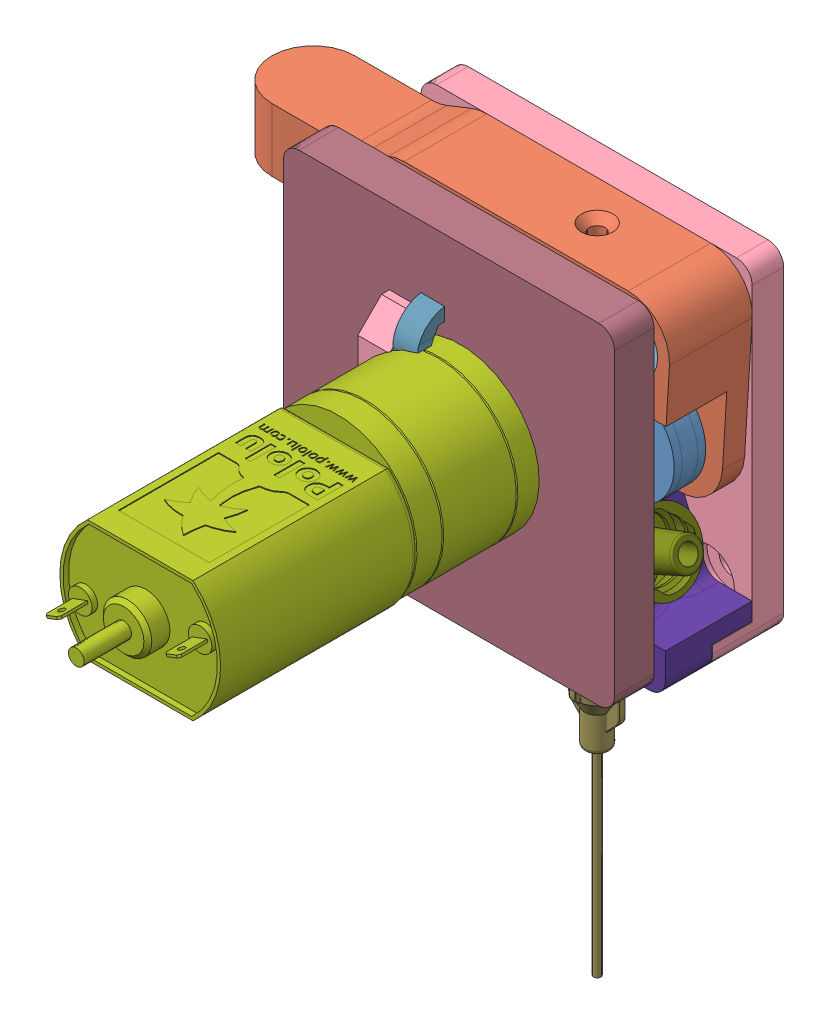
SolidWorks assembly Extruder mini gear motor custom metal liner, configuration Default. Lengths in mm.
Overall size (55.67 53.4 45.47).
19 component instances, 17 part files, 38 mates.
Components (placement in the parent):
- ExtruderCR10 idler-1: ExtruderCR10 idler [Default] at (-21 -21 0) size (13 13 4)
- ExtruderCR10 lever-1: ExtruderCR10 lever [Default] at (-21 -21 0) size (55.67 26.5 10.5)
- ExtruderCR10 spring-1: ExtruderCR10 spring [Default] at (-21 -21 0) size (8.03 21.41 8.04)
- Extruder custom base-1: Extruder custom base [Default] at origin size (42 42 24)
- ExtruderCR10 bushing-1: ExtruderCR10 bushing [Default] at (-21 -21 0) size (8 8 10.5)
- ExtruderCR10 M3-1: ExtruderCR10 M3 [Default] at (-21 -21 0) size (5.58 5.58 7.43)
- 20d-metal-gearmotor-25-31-with-extended-motor-shaft-1: 20d-metal-gearmotor-25-31-with-extended-motor-shaft [Default] at (23.8942 -21.0034 65.0067) x (-1 0 0) z (0 0 -1) size (20.4 20 67.2) (hidden)
- Part1-1: Part1 [Default] at (0 0 -19.7668) size (11.5 11.5 6)
- 94510A360_BRASS SCREW-TO-EXPAND INSERTS FOR PLASTICS-1: 94510A360_BRASS SCREW-TO-EXPAND INSERTS FOR PLASTICS [94510A360] at (-0.5 -16 0) x (0 -1 0) z (1 0 0) size (4.8 4.14 4.77) (hidden)
- 94510A240_BRASS SCREW-TO-EXPAND INSERTS-1: 94510A240_BRASS SCREW-TO-EXPAND INSERTS [94510A240] at (-0.5 -16 0) x (0 1 0) z (-1 0 0) size (5.54 5.05 5.54)
- 52335K910_METRIC EXTREME-TEMP TUBING MADE WITH PTFE-1: 52335K910_METRIC EXTREME-TEMP TUBING MADE WITH PTFE [52335K91] at (6.35 -9.5 9) x (0 1 0) z (0.546944 0 -0.837169) size (15 3 3)
- Syringe Needle, With Luer-1: Syringe Needle, With Luer [Yellow_20Gauge] at (6.35 -36.1851 9) x (0 1 0) z (0 0 1) size (43.15 7.7 8.15) (hidden)
- Part3-1: Part3 [Default] at (121.6474 -10.6831 -30.0878) size (42 42 5) (hidden)
- micro-metal-gearmotor-extended-with-1086-bracket (1)-1: micro-metal-gearmotor-extended-with-1086-bracket (1) [Default] at (0 0 24.27) x (0 0 -1) z (0 -1 0) size (39.3 11.72 26.5)
- Syringe Needle, Without Luer-1: Syringe Needle, Without Luer [Yellow_20Gauge] at (6.35 -7 9) x (0 1 0) z (-0.546944 0 0.837169) size (30.9 0.91 0.91)
- Manifold-1: Manifold [Default] at origin size (27 20.23 11)
  - Luer male-1: Luer male [Default] at (17.8808 -9.5965 9) x (0.923028 0.384734 0) z (0 0 1) size (8.55 9.27 9.27)
  - Luer male-2: Luer male [Default] at (6.35 -25.5471 9) x (0 -1 0) z (0 0 1) size (8.55 9.27 9.27)
  - Part2-1: Part2 [Default] at origin size (27 14.5 11)
Mates (geometry in assembly coordinates):
- Concentric1: concentric anti-aligned: cylinder of ExtruderCR10 lever-1 through (15.5 15.5 4) axis (0 0 1) radius 2.5; cylinder of ExtruderCR10 bushing-1 through (15.5 15.5 4) axis (0 0 -1) radius 1.6
- Coincident1: coincident aligned: plane of ExtruderCR10 lever-1 through (14.552 0 4) normal (0 0 -1); plane of ExtruderCR10 bushing-1 through (17.1 15.5 4) normal (0 0 -1)
- Concentric2: concentric anti-aligned: cylinder of Extruder custom base-1 through (15.5 15.5 4) axis (0 0 1) radius 1.7; cylinder of ExtruderCR10 bushing-1 through (15.5 15.5 4) axis (0 0 -1) radius 1.6
- Coincident2: coincident anti-aligned: plane of ExtruderCR10 lever-1 through (14.552 0 4) normal (0 0 -1); plane of Extruder custom base-1 through (0 0 4) normal (0 0 1)
- Concentric3: concentric aligned: cylinder of ExtruderCR10 idler-1 through (11.6075 1 10.8172) axis (0 0 1) radius 1.6; cylinder of ExtruderCR10 lever-1 through (11.6075 1 4) axis (0 0 1) radius 1.75
- Coincident3: coincident anti-aligned: plane of ExtruderCR10 idler-1 through (13.2075 1 7) normal (0 0 -1); plane of ExtruderCR10 lever-1 through (11.6075 1 7) normal (0 0 1)
- Concentric4: concentric anti-aligned: cylinder of ExtruderCR10 lever-1 through (11.6075 1 4) axis (0 0 1) radius 1.75; cylinder of ExtruderCR10 M3-1 through (11.6075 1 5) axis (0 0 -1) radius 1.5
- Coincident4: coincident anti-aligned: plane of ExtruderCR10 idler-1 through (18.1075 1 11) normal (0 0 1); plane of ExtruderCR10 M3-1 through (13.1075 1 11) normal (0 0 -1)
- Coincident5: coincident aligned: plane of ExtruderCR10 lever-1 through (21.3467 21 14.5) normal (0 1 0); plane of Extruder custom base-1 through (-21 21 4) normal (0 1 0)
- Concentric5: concentric anti-aligned: cylinder of Extruder custom base-1 through (0 0 0) axis (0 0 1) radius 5; cylinder of 20d-metal-gearmotor-25-31-with-extended-motor-shaft-1 through (0 0 19.5) axis (0 0 -1) radius 2
- Parallel1: parallel anti-aligned: plane of 20d-metal-gearmotor-25-31-with-extended-motor-shaft-1 through (23.8942 -21.0034 65.0067) normal (-1 0 0)
- Distance1: distance = 1.5 mm aligned: plane of 20d-metal-gearmotor-25-31-with-extended-motor-shaft-1 through (0 0 1.5) normal (0 0 -1); plane of Extruder custom base-1 through (0 0 0) normal (0 0 -1)
- Concentric6: concentric aligned: cylinder of 20d-metal-gearmotor-25-31-with-extended-motor-shaft-1 through (0 0 19.5) axis (0 0 -1) radius 2; cylinder of Part1-1 through (0 0 12) axis (0 0 -1) radius 2
- Width1: width anti-aligned: plane of Part1-1 through (0 0 6) normal (0 0 -1); plane of ExtruderCR10 idler-1 through (0 0 12) normal (0 0 1); plane of Part1-1 through (18.1075 1 11) normal (0 0 1); plane of ExtruderCR10 idler-1 through (13.2075 1 7) normal (0 0 -1)
- Coincident9: coincident aligned: plane of ExtruderCR10 base-1 through (-21 -21 4) normal (-1 0 0); plane of Extruder custom base-1 through (-21 -21 4) normal (-1 0 0)
- Coincident10: coincident aligned: plane of ExtruderCR10 base-1 through (-21 21 4) normal (0 1 0); plane of Extruder custom base-1 through (-21 21 4) normal (0 1 0)
- Coincident11: coincident aligned: plane of ExtruderCR10 base-1 through (-21 -21 0) normal (0 0 -1); plane of Extruder custom base-1 through (0 0 0) normal (0 0 -1)
- Concentric7: concentric anti-aligned: cylinder of ExtruderCR10 spring-1 through (-15 -6.4 9.5) axis (0 -1 0) radius 3; cylinder of Extruder custom base-1 through (-15 -21.001 9.5) axis (0 1 0) radius 1.25
- Coincident12: coincident anti-aligned: plane of ExtruderCR10 spring-1 through (-21 -6.5 9.5) normal (0 -1 0); plane of Extruder custom base-1 through (-21 -6.5 28.5) normal (0 1 0)
- Coincident13: coincident aligned: plane of Extruder custom base-1 through (0 0 0) normal (0 0 -1); plane of 94510A360_BRASS SCREW-TO-EXPAND INSERTS FOR PLASTICS-1 through (-0.5 -16 0) normal (0 0 -1)
- Parallel2: parallel anti-aligned: plane of 94510A360_BRASS SCREW-TO-EXPAND INSERTS FOR PLASTICS-1 through (-0.5 -16 0) normal (0 -1 0)
- Concentric8: concentric aligned: cylinder of Extruder custom base-1 through (-0.5 -16 15.001) axis (0 0 -1) radius 2.05; cylinder of 94510A360_BRASS SCREW-TO-EXPAND INSERTS FOR PLASTICS-1 through (-0.5 -16 0.5) axis (0 0 -1) radius 2.4
- Coincident15: coincident aligned: plane of 94510A240_BRASS SCREW-TO-EXPAND INSERTS-1 through (-3.2686 -16 0) normal (0 0 -1); plane of Extruder custom base-1 through (0 0 0) normal (0 0 -1)
- Concentric9: concentric aligned: cylinder of Extruder custom base-1 through (-0.5 -16 0.65) axis (0 0 -1) radius 2.8; cylinder of 94510A240_BRASS SCREW-TO-EXPAND INSERTS-1 through (-0.5 -16 0.6096) axis (0 0 -1) radius 2.7686
- Parallel3: parallel aligned: plane of 94510A240_BRASS SCREW-TO-EXPAND INSERTS-1 through (-0.5 -16 0) normal (0 1 0)
- Parallel6: parallel aligned: plane of Syringe Needle, With Luer-1 through (6.35 -36.1851 9) normal (0 0 1)
- Concentric14: concentric anti-aligned: cylinder of Part1-1 through (0 0 12) axis (0 0 -1) radius 2; cylinder of micro-metal-gearmotor-extended-with-1086-bracket (1)-1 through (0 0 5.27) axis (0 0 1) radius 1.5
- Parallel7: parallel anti-aligned: plane of Extruder custom base-1 through (-6.5 -11.5 24) normal (1 0 0); plane of micro-metal-gearmotor-extended-with-1086-bracket (1)-1 through (-5 -3.3166 39.27) normal (-1 0 0)
- Distance2: distance = 0 mm aligned: plane of micro-metal-gearmotor-extended-with-1086-bracket (1)-1 through (0 0 6) normal (0 0 -1); plane of Part1-1 through (0 0 6) normal (0 0 -1)
- Parallel8: parallel aligned: plane of Assem1^Extruder mini gear motor custom metal liner-1/Luer male-1 through (17.8808 -9.5965 9) normal (0 0 1)
- Parallel9: parallel aligned: plane of Assem1^Extruder mini gear motor custom metal liner-1/Luer male-2 through (6.35 -25.5471 9) normal (1 0 0)
- Coincident31: coincident anti-aligned: plane of Assem1^Extruder mini gear motor custom metal liner-1/Luer male-2 through (10.3505 -18.4351 9) normal (0 -1 0); plane of Syringe Needle, With Luer-1 through (4.3 -18.4351 9) normal (0 1 0)
- Concentric18: concentric anti-aligned: cylinder of Assem1^Extruder mini gear motor custom metal liner-1/Luer male-2 through (6.35 -17 9) axis (0 1 0) radius 1.1811; cylinder of Syringe Needle, With Luer-1 through (6.35 -30.6851 9) axis (0 -1 0) radius 0.32
- Coincident32: coincident anti-aligned: plane of Assem1^Extruder mini gear motor custom metal liner-1/Luer male-2 through (6.35 -17 9) normal (0 1 0); plane of 52335K910_METRIC EXTREME-TEMP TUBING MADE WITH PTFE-1 through (6.35 -17 9) normal (0 -1 0)
- Concentric19: concentric aligned: cylinder of Assem1^Extruder mini gear motor custom metal liner-1/Part2-1 through (6.35 -6.5 9) axis (0 -1 0) radius 1.5; cylinder of 52335K910_METRIC EXTREME-TEMP TUBING MADE WITH PTFE-1 through (6.35 -2 9) axis (0 -1 0) radius 1.5
- Coincident33: coincident anti-aligned: plane of Assem1^Extruder mini gear motor custom metal liner-1/Part2-1 through (14.552 0 15) normal (0 0 1); plane of Part3-1 through (121.6474 -10.6831 15) normal (0 0 -1)
- Distance4: distance = 5 mm aligned: plane of Assem1^Extruder mini gear motor custom metal liner-1/Part2-1 through (-6 -6.5 45.6472) normal (0 1 0); plane of Syringe Needle, Without Luer-1 through (6.35 -1.5 9) normal (0 1 0)
- Concentric20: concentric aligned: cylinder of Assem1^Extruder mini gear motor custom metal liner-1/Part2-1 through (6.35 -6.5 9) axis (0 -1 0) radius 1.5; cylinder of Syringe Needle, Without Luer-1 through (6.35 -1.5 9) axis (0 -1 0) radius 0.455
